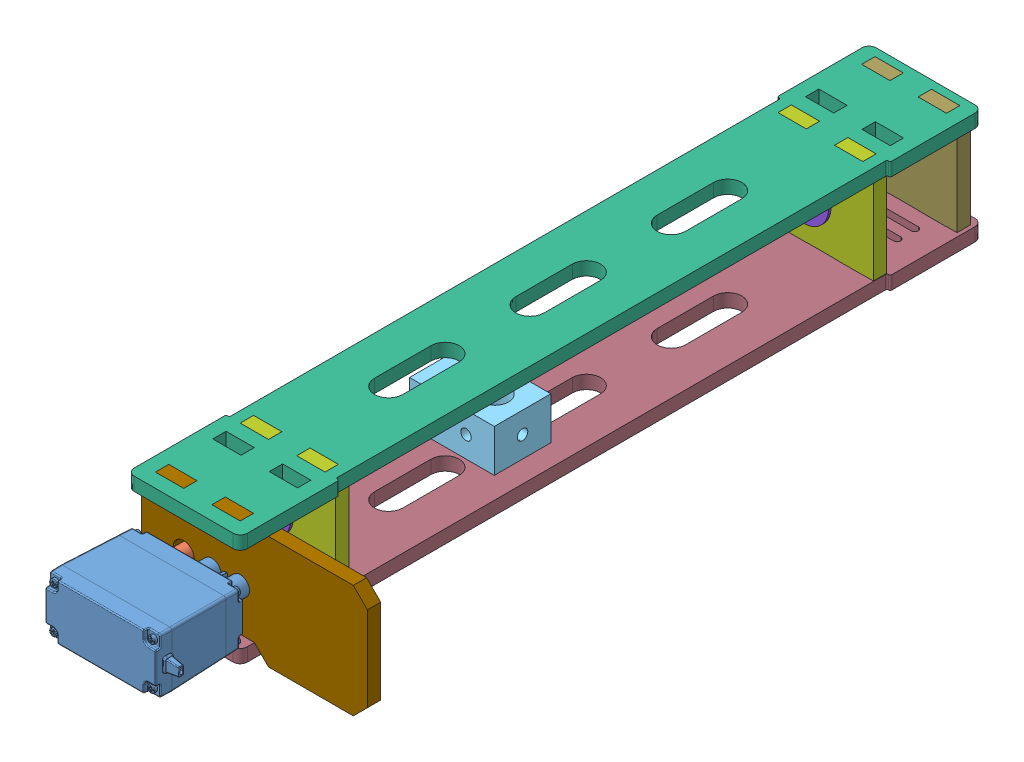
SolidWorks assembly Axis 1, configuration Default. Lengths in mm.
Overall size (101.6 50.8 385.81).
15 component instances, 13 part files, 41 mates.
Components (placement in the parent):
- 276-2177-1: 276-2177 [Default] at (-34.5901 9.5753 240.5294) x (-1 0 0) z (0 1 0) size (56.4 55.81 25)
- Square Shaft Adapter-1: Square Shaft Adapter [Default] at (-60.2901 9.5753 206.0294) x (-0.971099 -0.238678 0) z (0 0 -1) size (6.35 6.35 31.75)
- 95475A656-1: 95475A656 [95475A656] at (-60.2901 9.5753 28.2294) x (0.981691 0.190478 0) z (0 0 1) size (11 9.67 270.12)
- Threaded Rod Shaft Coupler-1: Threaded Rod Shaft Coupler [Default] at (-60.2901 9.5753 161.5794) x (1 0 0) z (0 -1 0) size (19.05 25.4 19.05)
- Adapter-1: Adapter [Default] at (-68.2276 9.5753 73.8865) x (0 -1 0) z (0 0 1) size (19.05 38.1 25.4)
- Side Plate-1: Side Plate [Default] at (-28.5401 28.6253 -102.4552) x (0 0 -1) z (0 1 0) size (333.38 50.8 5.99)
- Bearing Block-1: Bearing Block [Default] at (-60.2901 9.5753 -83.7608) x (0 -1 0) z (0 0 -1) size (50.09 47.62 5.99)
- Bearing-1: Bearing [Default] at (-60.2901 9.5753 -89.7552) size (22.23 22.23 7.11)
- Bearing Block-2: Bearing Block [Default] at (-60.2901 9.5753 151.9004) x (0 1 0) z (0 0 1) size (50.09 47.62 5.99)
- Bearing-2: Bearing [Default] at (-60.2901 9.5753 151.9004) size (22.23 22.23 7.11)
- Motor Block-1: Motor Block [Default] at (-28.5401 28.6253 190.0004) x (0 1 0) z (0 0 1) size (50.8 101.6 5.99)
- Position Sensor-1: Position Sensor [Default] at (-60.2901 9.5753 -138.2676) x (0.975862 0.218387 0) z (0.218387 -0.975862 0) size (19.05 33.15 19.05)
- Position Sensor Adapter-1: Position Sensor Adapter [Default] at (-60.2901 9.5753 -94.0081) x (0.787081 0.616849 0) z (-0.616849 0.787081 0) size (12.7 17.46 12.7)
- Sensor Block-1: Sensor Block [Default] at (-28.5401 28.6253 -127.3456) x (0 1 0) z (0 0 1) size (50.09 47.62 5.99)
- Side Plate 2-2: Side Plate 2 [Default] at (-28.5401 -15.5523 -102.4552) x (0 0 -1) z (0 1 0) size (333.38 50.8 5.99)
Mates (geometry in assembly coordinates):
- Concentric1: concentric anti-aligned: circle of 95475A656-1; cylinder of Threaded Rod Shaft Coupler-1 through (-60.2901 9.5753 186.9794) axis (0 0 -1) radius 3.302
- Coincident1: coincident anti-aligned: plane of 95475A656-1 through (-60.2901 9.5753 161.5794) normal (0 0 1); plane of Threaded Rod Shaft Coupler-1 through (-60.2901 9.5753 161.5794) normal (0 0 -1)
- Concentric2: concentric anti-aligned: cylinder of Square Shaft Adapter-1 through (-60.2901 9.5753 174.2794) axis (0 0 1) radius 3.175; cylinder of Threaded Rod Shaft Coupler-1 through (-60.2901 9.5753 186.9794) axis (0 0 -1) radius 3.302
- Coincident6: coincident anti-aligned: plane of 276-2177-1 through (-60.2901 9.5753 206.0294) normal (0 0 -1); plane of Square Shaft Adapter-1 through (-60.2901 9.5753 206.0294) normal (0 0 1)
- Concentric5: concentric aligned: circle of 276-2177-1; cylinder of Square Shaft Adapter-1 through (-60.2901 9.5753 174.2794) axis (0 0 1) radius 3.175
- Concentric6: concentric anti-aligned: circle of 95475A656-1; cylinder of Adapter-1 through (-60.2901 9.5753 61.1865) axis (0 0 1) radius 4.7625
- Coincident8: coincident anti-aligned: plane of Side Plate-1 through (-47.5901 34.6197 -83.7608) normal (1 0 0); plane of Bearing Block-1 through (-47.5901 28.6253 -89.7552) normal (-1 0 0)
- Coincident11: coincident anti-aligned: plane of Side Plate-1 through (-28.5401 28.6253 -102.4552) normal (0 -1 0); plane of Bearing Block-1 through (-34.8901 28.6253 -89.7552) normal (0 1 0)
- Concentric7: concentric anti-aligned: cylinder of Bearing Block-1 through (-60.2901 9.5753 -89.7552) axis (0 0 1) radius 11.1125; cylinder of Bearing-1 through (-60.2901 9.5753 -82.6432) axis (0 0 -1) radius 4.7625
- Concentric8: concentric aligned: circle of 95475A656-1; cylinder of Bearing-1 through (-60.2901 9.5753 -82.6432) axis (0 0 -1) radius 4.7625
- Parallel2: parallel anti-aligned: plane of Adapter-1 through (-30.1276 19.1003 86.5865) normal (0 1 0); plane of Side Plate-1 through (-28.5401 28.6253 -102.4552) normal (0 -1 0)
- Coincident15: coincident aligned: plane of Bearing Block-1 through (-60.2901 9.5753 -89.7552) normal (0 0 -1); plane of Bearing-1 through (-60.2901 9.5753 -89.7552) normal (0 0 -1)
- Distance3: distance = 12.7 mm anti-aligned: plane of Threaded Rod Shaft Coupler-1 through (-60.2901 9.5753 186.9794) normal (0 0 1); plane of Square Shaft Adapter-1 through (-60.2901 9.5753 174.2794) normal (0 0 -1)
- Concentric9: concentric aligned: cylinder of Bearing Block-2 through (-60.2901 9.5753 157.8948) axis (0 0 -1) radius 11.1125; cylinder of Bearing-2 through (-60.2901 9.5753 159.0124) axis (0 0 -1) radius 11.1125
- Coincident17: coincident aligned: plane of Bearing Block-2 through (-60.2901 9.5753 151.9004) normal (0 0 -1); plane of Bearing-2 through (-60.2901 9.5753 151.9004) normal (0 0 -1)
- Coincident18: coincident anti-aligned: plane of Side Plate-1 through (-28.5401 28.6253 -102.4552) normal (0 -1 0); plane of Bearing Block-2 through (-60.2901 28.6253 157.8948) normal (0 1 0)
- Coincident19: coincident anti-aligned: plane of Side Plate-1 through (-72.9901 34.6197 157.8948) normal (0 0 -1); plane of Bearing Block-2 through (-60.2901 9.5753 157.8948) normal (0 0 1)
- Concentric10: concentric aligned: circle of 95475A656-1; cylinder of Bearing-2 through (-60.2901 9.5753 159.0124) axis (0 0 -1) radius 4.7625
- Parallel3: parallel: line of 276-2177-1 through (-70.0901 -2.9247 240.5294) axis (1 0 0); plane of Side Plate-1 through (-28.5401 28.6253 -102.4552) normal (0 -1 0)
- Coincident22: coincident anti-aligned: plane of Side Plate-1 through (-28.5401 28.6253 -102.4552) normal (0 -1 0); plane of Motor Block-1 through (-47.5901 28.6253 195.9948) normal (0 1 0)
- Coincident23: coincident anti-aligned: plane of Side Plate-1 through (-47.5901 34.6197 195.9948) normal (0 0 -1); plane of Motor Block-1 through (-28.5401 28.6253 195.9948) normal (0 0 1)
- Coincident24: coincident anti-aligned: plane of Side Plate-1 through (-34.8901 34.6197 195.9948) normal (-1 0 0); plane of Motor Block-1 through (-34.8901 28.6253 195.9948) normal (1 0 0)
- Parallel4: parallel aligned: plane of Side Plate-1 through (-28.5401 34.6197 -102.4552) normal (1 0 0); plane of assembly through (0 0 0) normal (1 0 0)
- Concentric11: concentric aligned: circle of 95475A656-1; cylinder of Position Sensor-1 through (-60.2901 9.5753 -105.1206) axis (0 0 -1) radius 3.175
- Coincident25: coincident anti-aligned: plane of 95475A656-1 through (-60.2901 9.5753 -105.1206) normal (0 0 -1); plane of Position Sensor-1 through (-60.2901 9.5753 -105.1206) normal (0 0 1)
- Concentric13: concentric anti-aligned: circle of 95475A656-1; cylinder of Position Sensor Adapter-1 through (-60.2901 9.5753 -105.1206) axis (0 0 1) radius 4.7625
- Coincident26: coincident anti-aligned: plane of 95475A656-1 through (-60.2901 9.5753 -105.1206) normal (0 0 -1); plane of Position Sensor Adapter-1 through (-60.2901 9.5753 -105.1206) normal (0 0 1)
- Coincident27: coincident anti-aligned: plane of Side Plate-1 through (-28.5401 28.6253 -102.4552) normal (0 -1 0); plane of Sensor Block-1 through (-47.5901 28.6253 -121.3512) normal (0 1 0)
- Coincident29: coincident anti-aligned: plane of Position Sensor-1 through (-60.2901 9.5753 -127.3456) normal (0 0 1); plane of Sensor Block-1 through (-28.5401 28.6253 -127.3456) normal (0 0 -1)
- Concentric14: concentric anti-aligned: cylinder of Position Sensor-1 through (-60.2901 9.5753 -117.8206) axis (0 0 -1) radius 4.7625; cylinder of Sensor Block-1 through (-60.2901 9.5753 -127.3456) axis (0 0 1) radius 4.7244
- Coincident30: coincident aligned: plane of Side Plate-1 through (-30.0276 28.6253 157.8949) normal (1 0 0); plane of ? through (-30.0276 -15.4691 157.8949) normal (1 0 0)
- Parallel5: parallel anti-aligned: plane of Side Plate-1 through (-28.5401 28.6253 -102.4551) normal (0 -1 0); plane of ? through (-28.5401 -9.4747 -102.4551) normal (0 1 0)
- Coincident32: coincident anti-aligned: plane of Sensor Block-1 through (-47.5901 -9.4747 -121.3512) normal (0 -1 0); plane of ? through (-28.5401 -9.4747 -102.4551) normal (0 1 0)
- Coincident33: coincident aligned: plane of Side Plate-1 through (-79.3401 -29.6599 -131.0301) normal (0 0 -1); plane of ? through (-79.3401 -73.7543 -131.0301) normal (0 0 -1)
- Coincident34: coincident aligned: plane of Side Plate-1 through (-30.0276 28.6253 157.8948) normal (1 0 0); plane of Side Plate 2-2 through (-30.0276 -15.5523 157.8948) normal (1 0 0)
- Parallel6: parallel anti-aligned: plane of Side Plate-1 through (-28.5401 28.6253 -102.4552) normal (0 -1 0); plane of Side Plate 2-2 through (-28.5401 -9.5579 -102.4552) normal (0 1 0)
- Coincident38: coincident aligned: plane of Side Plate-1 through (-79.3401 -29.6599 -131.0302) normal (0 0 -1); plane of Side Plate 2-2 through (-79.3401 -73.8376 -131.0302) normal (0 0 -1)
- Coincident42: coincident anti-aligned: plane of Side Plate-1 through (-47.5901 28.6253 -127.3456) normal (0 0 1); plane of Sensor Block-1 through (-28.5401 28.6253 -127.3456) normal (0 0 -1)
- Coincident43: coincident anti-aligned: plane of Side Plate-1 through (-47.5901 34.6197 -89.7552) normal (0 0 1); plane of Bearing Block-1 through (-60.2901 9.5753 -89.7552) normal (0 0 -1)
- Coincident44: coincident anti-aligned: plane of Adapter-1 through (-30.1276 9.5753 73.8865) normal (1 0 0); plane of ? through (-30.1276 15.9253 73.8865) normal (-1 0 0)
- Concentric15: concentric aligned: cylinder of Adapter-1 through (-68.2286 9.5753 73.8865) axis (1 0 0) radius 2.3495; cylinder of ? through (-30.1276 9.5753 73.8865) axis (1 0 0) radius 2.413
